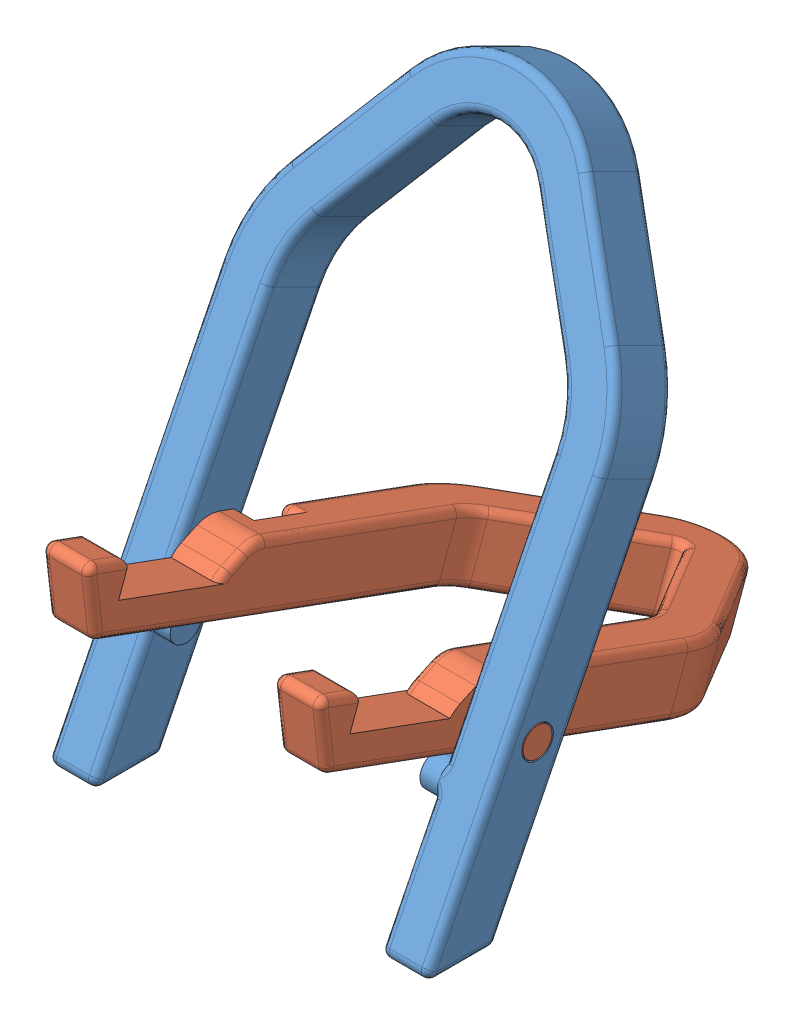
SolidWorks assembly Assem2, configuration Default. Lengths in mm.
Overall size (76.2 118.43 113.06).
2 component instances, 2 part files, 5 mates.
Components (placement in the parent):
- Outer-1: Outer [Default] at (0 -5.6796 -10.2564) x (1 0 0) z (0 0.447214 0.894427) size (76.2 126.06 12.7)
- Inner-1: Inner [Default] at (0 38.3698 16.3457) x (1 0 0) z (0 0.939078 -0.343703) size (76.2 115.75 12.7)
Mates (geometry in assembly coordinates):
- Concentric1: concentric aligned: cylinder of Outer-1 through (-38.1 31.2379 -21.6157) axis (1 0 0) radius 3.175; cylinder of Inner-1 through (-38.1 31.2379 -21.6157) axis (1 0 0) radius 2.921
- Width1: width aligned: plane of Outer-1 through (38.1 79.5146 -38.6545) normal (1 0 0); plane of Inner-1 through (-38.1 79.5146 -38.6545) normal (-1 0 0); plane of Outer-1 through (27.94 40.1257 15.9734) normal (1 0 0); plane of Inner-1 through (-27.94 40.1257 15.9734) normal (-1 0 0)
- Coincident1: coincident aligned: plane of Outer-1 through (0 -5.6796 -10.2564) normal (1 0 0)
- Coincident2: coincident anti-aligned: plane of Outer-1 through (-38.1 0 1.1028) normal (0 -1 0)
- Coincident3: coincident: line of Outer-1 through (-36.576 2.2056 0) axis (1 0 0)
